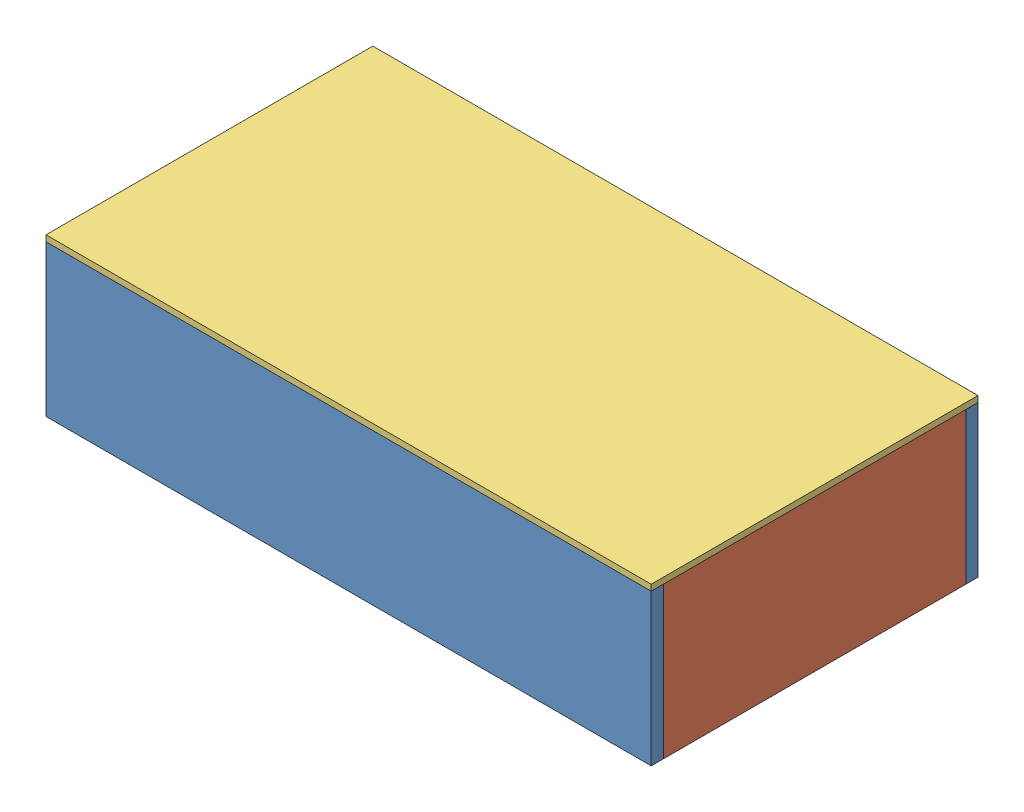
SolidWorks assembly Assem1, configuration Default. Lengths in mm.
Overall size (1000 260 540).
5 component instances, 3 part files, 12 mates.
Components (placement in the parent):
- LengthPanel-1: LengthPanel [Default] at (498.2133 647.727 616.1406) size (1000 250 20)
- LengthPanel-2: LengthPanel [Default] at (498.2133 647.727 1136.1406) size (1000 250 20)
- Widthpanel-1: Widthpanel [Default] at (998.2133 647.727 886.1406) x (0 0 1) z (-1 0 0) size (500 250 20)
- Widthpanel-2: Widthpanel [Default] at (-1.7867 647.727 886.1406) x (0 0 -1) z (1 0 0) size (500 250 20)
- BottomPlate-1: BottomPlate [Default] at (498.2133 772.727 886.1406) size (1000 10 540)
Mates (geometry in assembly coordinates):
- Coincident2: coincident: plane of LengthPanel-1 through (498.2133 647.727 636.1406) normal (0 0 1); plane of Widthpanel-2 through (18.2133 522.727 636.1406) normal (0 0 -1)
- Coincident3: coincident: plane of LengthPanel-1 through (-1.7867 772.727 636.1406) normal (0 1 0); plane of Widthpanel-2 through (18.2133 772.727 1136.1406) normal (0 1 0)
- Coincident4: coincident aligned: plane of LengthPanel-1 through (-1.7867 522.727 636.1406) normal (-1 0 0); plane of Widthpanel-2 through (-1.7867 647.727 886.1406) normal (-1 0 0)
- Coincident5: coincident: plane of LengthPanel-2 through (498.2133 647.727 1136.1406) normal (0 0 -1); plane of Widthpanel-2 through (18.2133 522.727 1136.1406) normal (0 0 1)
- Coincident6: coincident: plane of LengthPanel-2 through (-1.7867 772.727 1156.1406) normal (0 1 0); plane of Widthpanel-2 through (18.2133 772.727 1136.1406) normal (0 1 0)
- Coincident7: coincident aligned: plane of LengthPanel-2 through (-1.7867 522.727 1156.1406) normal (-1 0 0); plane of Widthpanel-2 through (-1.7867 647.727 886.1406) normal (-1 0 0)
- Coincident8: coincident: plane of LengthPanel-1 through (498.2133 647.727 636.1406) normal (0 0 1); plane of Widthpanel-1 through (978.2133 522.727 636.1406) normal (0 0 -1)
- Coincident9: coincident: plane of LengthPanel-1 through (-1.7867 772.727 636.1406) normal (0 1 0); plane of Widthpanel-1 through (978.2133 772.727 636.1406) normal (0 1 0)
- Coincident10: coincident aligned: plane of LengthPanel-1 through (998.2133 522.727 636.1406) normal (1 0 0); plane of Widthpanel-1 through (998.2133 647.727 886.1406) normal (1 0 0)
- Coincident11: coincident: plane of LengthPanel-1 through (-1.7867 772.727 636.1406) normal (0 1 0); plane of BottomPlate-1 through (498.2133 772.727 886.1406) normal (0 -1 0)
- Coincident12: coincident: line of LengthPanel-1 through (998.2133 772.727 616.1406) axis (-1 0 0); line of BottomPlate-1 through (998.2133 772.727 616.1406) axis (-1 0 0)
- Coincident13: coincident aligned: line of Widthpanel-2 through (-1.7867 772.727 636.1406) axis (0 0 1); line of BottomPlate-1 through (-1.7867 772.727 616.1406) axis (0 0 1)
